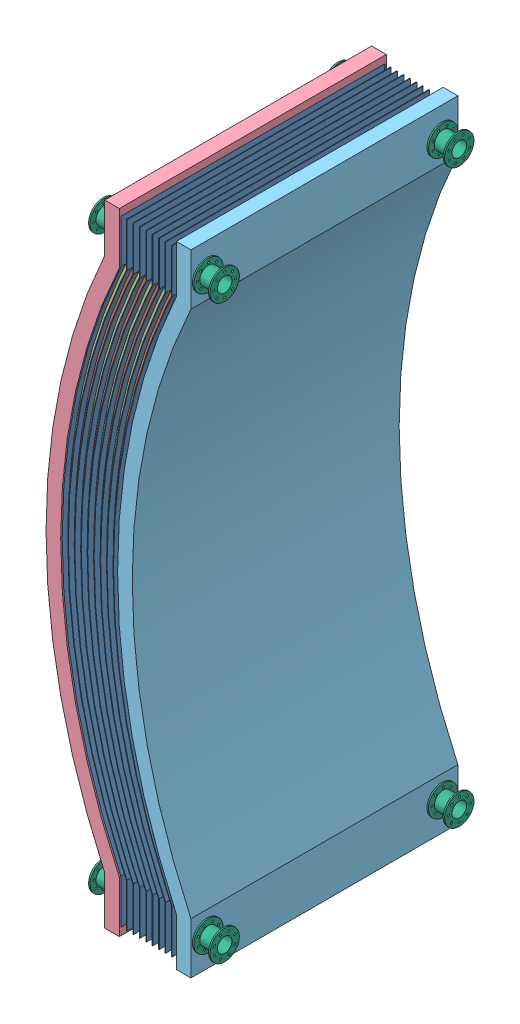
SolidWorks assembly final assembly, configuration Default. Lengths in mm.
Overall size (281.48 1092.2 476.71).
37 component instances, 6 part files, 29 mates.
Components (placement in the parent):
- curved assembly-1: curved assembly [Default] at (-66.7836 46.4861 -15.4947) size (146.36 1066.8 457.2)
  - plate 2-1: plate 2 [Default] at (574.3501 1020.4927 597.4906) size (105.22 1066.8 457.2)
  - plate 2-2: plate 2 [Default] at (585.5261 1020.4927 597.4906) size (105.22 1066.8 457.2)
  - gasket 4-1: gasket 4 [Default] at (584.5101 925.4498 597.4906) size (111.81 1021.08 436.88)
  - plate 2-3: plate 2 [Default] at (596.7021 1020.4927 597.4906) size (105.22 1066.8 457.2)
  - gasket 3-2: gasket 3 [Default] at (595.6861 925.4498 597.4906) size (111.81 1021.08 436.88)
  - plate 2-4: plate 2 [Default] at (607.8781 1020.4927 597.4906) size (105.22 1066.8 457.2)
  - gasket 4-2: gasket 4 [Default] at (606.8621 925.4498 597.4906) size (111.81 1021.08 436.88)
  - gasket 3-3: gasket 3 [Default] at (573.3341 925.4498 597.4906) size (111.81 1021.08 436.88)
- curved assembly-2: curved assembly [Default] at (-22.0796 46.4861 -15.4947) size (146.36 1066.8 457.2)
  - plate 2-1: plate 2 [Default] at (574.3501 1020.4927 597.4906) size (105.22 1066.8 457.2)
  - plate 2-2: plate 2 [Default] at (585.5261 1020.4927 597.4906) size (105.22 1066.8 457.2)
  - gasket 4-1: gasket 4 [Default] at (584.5101 925.4498 597.4906) size (111.81 1021.08 436.88)
  - plate 2-3: plate 2 [Default] at (596.7021 1020.4927 597.4906) size (105.22 1066.8 457.2)
  - gasket 3-2: gasket 3 [Default] at (595.6861 925.4498 597.4906) size (111.81 1021.08 436.88)
  - plate 2-4: plate 2 [Default] at (607.8781 1020.4927 597.4906) size (105.22 1066.8 457.2)
  - gasket 4-2: gasket 4 [Default] at (606.8621 925.4498 597.4906) size (111.81 1021.08 436.88)
  - gasket 3-3: gasket 3 [Default] at (573.3341 925.4498 597.4906) size (111.81 1021.08 436.88)
- curved assembly-3: curved assembly [Default] at (22.6244 46.4861 -15.4947) size (146.36 1066.8 457.2)
  - plate 2-1: plate 2 [Default] at (574.3501 1020.4927 597.4906) size (105.22 1066.8 457.2)
  - plate 2-2: plate 2 [Default] at (585.5261 1020.4927 597.4906) size (105.22 1066.8 457.2)
  - gasket 4-1: gasket 4 [Default] at (584.5101 925.4498 597.4906) size (111.81 1021.08 436.88)
  - plate 2-3: plate 2 [Default] at (596.7021 1020.4927 597.4906) size (105.22 1066.8 457.2)
  - gasket 3-2: gasket 3 [Default] at (595.6861 925.4498 597.4906) size (111.81 1021.08 436.88)
  - plate 2-4: plate 2 [Default] at (607.8781 1020.4927 597.4906) size (105.22 1066.8 457.2)
  - gasket 4-2: gasket 4 [Default] at (606.8621 925.4498 597.4906) size (111.81 1021.08 436.88)
  - gasket 3-3: gasket 3 [Default] at (573.3341 925.4498 597.4906) size (111.81 1021.08 436.88)
- outer 1-1: outer 1 [Default] at (519.2505 971.9359 579.4559) size (127.05 1092.2 462.28)
- outer 2-1: outer 2 [Default] at (643.2025 971.9359 579.4559) size (127.05 1092.2 462.28)
- washer-1: washer [Default] at (465.9105 1010.0359 607.3959) x (0 -0.477528 0.878616) z (-1 0 0) size (50.8 50.8 30.48)
- washer-2: washer [Default] at (465.9105 1010.0359 1013.7959) x (0 -0.747117 0.664692) z (-1 0 0) size (50.8 50.8 30.48)
- washer-3: washer [Default] at (465.9105 19.4359 607.3959) x (0 -0.176929 0.984224) z (-1 0 0) size (50.8 50.8 30.48)
- washer-4: washer [Default] at (465.9105 19.4359 1013.7959) x (0 -0.798753 -0.601659) z (-1 0 0) size (50.8 50.8 30.48)
- washer-5: washer [Default] at (645.7425 1010.0359 1013.7959) x (0 0 1) z (-1 0 0) size (50.8 50.8 30.48)
- washer-6: washer [Default] at (645.7425 1010.0359 607.3959) x (0 -0.414936 0.909851) z (-1 0 0) size (50.8 50.8 30.48)
- washer-7: washer [Default] at (645.7425 19.4359 1013.7959) x (0 -0.38838 0.921499) z (-1 0 0) size (50.8 50.8 30.48)
- washer-8: washer [Default] at (645.7425 19.4359 607.3959) x (0 0.023986 0.999712) z (-1 0 0) size (50.8 50.8 30.48)
Mates (geometry in assembly coordinates):
- Concentric1: concentric: cylinder of assembly; cylinder of assembly; cylinder of curved assembly-1/gasket 4-2 through (82.8785 1010.0359 607.3959) axis (1 0 0) radius 15.24; cylinder of curved assembly-2/gasket 3-3 through (94.0545 1010.0359 607.3959) axis (1 0 0) radius 15.24
- Concentric2: concentric: cylinder of assembly; cylinder of assembly; cylinder of curved assembly-1/gasket 4-2 through (82.8785 1010.0359 1013.7959) axis (1 0 0) radius 15.24; cylinder of curved assembly-2/gasket 3-3 through (94.0545 1010.0359 1013.7959) axis (1 0 0) radius 15.24
- Coincident1: coincident: plane of assembly; plane of assembly; plane of curved assembly-1/plate 2-4 through (541.0945 1048.1359 1039.1959) normal (1 0 0); plane of curved assembly-2/gasket 3-3 through (541.0945 974.1893 1039.1959) normal (-1 0 0)
- Concentric3: concentric: cylinder of assembly; cylinder of assembly; cylinder of curved assembly-2/gasket 4-2 through (127.5825 1010.0359 1013.7959) axis (1 0 0) radius 15.24; cylinder of curved assembly-3/gasket 3-3 through (138.7585 1010.0359 1013.7959) axis (1 0 0) radius 15.24
- Concentric4: concentric: cylinder of assembly; cylinder of assembly; cylinder of curved assembly-2/gasket 4-2 through (127.5825 1010.0359 607.3959) axis (1 0 0) radius 15.24; cylinder of curved assembly-3/gasket 3-3 through (138.7585 1010.0359 607.3959) axis (1 0 0) radius 15.24
- Coincident2: coincident: plane of assembly; plane of assembly; plane of curved assembly-2/plate 2-4 through (585.7985 1048.1359 1039.1959) normal (1 0 0); plane of curved assembly-3/gasket 3-3 through (585.7985 974.1893 1039.1959) normal (-1 0 0)
- Concentric5: concentric: cylinder of assembly; cylinder of assembly; cylinder of curved assembly-1/gasket 4-1 through (964.7665 1010.0359 607.3959) axis (-1 0 0) radius 12.7; cylinder of outer 1-1 through (519.2505 1010.0359 607.3959) axis (-1 0 0) radius 12.7
- Coincident3: coincident: plane of assembly; plane of assembly; plane of curved assembly-1/plate 2-1 through (506.5505 1048.1359 1039.1959) normal (0 1 0); plane of outer 1-1 through (506.5505 1048.1359 1039.1959) normal (0 -1 0)
- Coincident4: coincident: plane of assembly; plane of assembly; plane of curved assembly-1/plate 2-1 through (506.5505 1048.1359 1039.1959) normal (-1 0 0); plane of outer 1-1 through (506.5505 974.7509 1039.1959) normal (1 0 0)
- Concentric8: concentric: cylinder of assembly; cylinder of assembly; cylinder of curved assembly-3/plate 2-4 through (1086.6865 1010.0359 1013.7959) axis (-1 0 0) radius 12.7; cylinder of outer 2-1 through (643.2025 1010.0359 1013.7959) axis (-1 0 0) radius 12.7
- Concentric9: concentric: cylinder of assembly; circle of assembly; cylinder of curved assembly-3/gasket 4-2 through (1076.5265 1010.0359 607.3959) axis (-1 0 0) radius 12.7; circle of outer 2-1
- Parallel2: parallel: plane of assembly; plane of assembly; plane of curved assembly-3/plate 2-4 through (629.4865 1048.1359 1039.1959) normal (0 1 0); plane of outer 2-1 through (617.8025 1060.8359 1041.7359) normal (0 1 0)
- Coincident7: coincident: plane of assembly; plane of assembly; plane of curved assembly-3/plate 2-4 through (630.5025 1048.1359 1039.1959) normal (1 0 0); plane of outer 2-1 through (630.5025 974.7509 1039.1959) normal (-1 0 0)
- Concentric10: concentric: cylinder of assembly; cylinder of assembly; cylinder of outer 1-1 through (519.2505 1010.0359 607.3959) axis (-1 0 0) radius 12.7; cylinder of washer-1 through (463.3705 1010.0359 607.3959) axis (1 0 0) radius 12.7
- Concentric11: concentric: cylinder of assembly; cylinder of assembly; cylinder of outer 1-1 through (519.2505 1010.0359 1013.7959) axis (-1 0 0) radius 12.7; cylinder of washer-2 through (463.3705 1010.0359 1013.7959) axis (1 0 0) radius 12.7
- Coincident11: coincident: plane of assembly; plane of assembly; plane of outer 1-1 through (493.8505 977.5488 1041.7359) normal (-1 0 0); plane of washer-1 through (493.8505 1010.0359 607.3959) normal (1 0 0)
- Coincident12: coincident: plane of assembly; plane of assembly; plane of outer 1-1 through (493.8505 977.5488 1041.7359) normal (-1 0 0); plane of washer-2 through (493.8505 1010.0359 1013.7959) normal (1 0 0)
- Concentric12: concentric: cylinder of assembly; cylinder of assembly; cylinder of curved assembly-1/gasket 4-1 through (964.7665 19.4359 607.3959) axis (-1 0 0) radius 12.7; cylinder of washer-3 through (463.3705 19.4359 607.3959) axis (1 0 0) radius 12.7
- Coincident13: coincident: plane of assembly; plane of assembly; plane of outer 1-1 through (493.8505 51.9229 1041.7359) normal (-1 0 0); plane of washer-3 through (493.8505 19.4359 607.3959) normal (1 0 0)
- Concentric13: concentric: cylinder of assembly; cylinder of assembly; cylinder of curved assembly-1/gasket 4-1 through (964.7665 19.4359 1013.7959) axis (-1 0 0) radius 12.7; cylinder of washer-4 through (463.3705 19.4359 1013.7959) axis (1 0 0) radius 12.7
- Coincident15: coincident: plane of assembly; plane of assembly; plane of outer 1-1 through (493.8505 51.9229 1041.7359) normal (-1 0 0); plane of washer-4 through (493.8505 19.4359 1013.7959) normal (1 0 0)
- Concentric14: concentric: cylinder of assembly; cylinder of assembly; cylinder of outer 2-1 through (643.2025 1010.0359 1013.7959) axis (-1 0 0) radius 12.7; cylinder of washer-5 through (643.2025 1010.0359 1013.7959) axis (1 0 0) radius 12.7
- Coincident16: coincident: plane of assembly; plane of assembly; plane of outer 2-1 through (643.2025 971.9359 1041.7359) normal (1 0 0); plane of washer-5 through (643.2025 1010.0359 1013.7959) normal (-1 0 0)
- Concentric15: concentric: cylinder of assembly; cylinder of assembly; cylinder of outer 2-1 through (643.2025 1010.0359 607.3959) axis (-1 0 0) radius 12.7; cylinder of washer-6 through (643.2025 1010.0359 607.3959) axis (1 0 0) radius 12.7
- Coincident18: coincident: plane of assembly; plane of assembly; plane of outer 2-1 through (643.2025 971.9359 1041.7359) normal (1 0 0); plane of washer-6 through (643.2025 1010.0359 607.3959) normal (-1 0 0)
- Concentric16: concentric: cylinder of assembly; cylinder of assembly; cylinder of outer 2-1 through (643.2025 19.4359 1013.7959) axis (-1 0 0) radius 12.7; cylinder of washer-7 through (643.2025 19.4359 1013.7959) axis (1 0 0) radius 12.7
- Coincident19: coincident: plane of assembly; plane of assembly; plane of outer 2-1 through (643.2025 57.5359 1041.7359) normal (1 0 0); plane of washer-7 through (643.2025 19.4359 1013.7959) normal (-1 0 0)
- Concentric17: concentric: cylinder of assembly; cylinder of assembly; cylinder of outer 2-1 through (643.2025 19.4359 607.3959) axis (-1 0 0) radius 12.7; cylinder of washer-8 through (643.2025 19.4359 607.3959) axis (1 0 0) radius 12.7
- Coincident20: coincident: plane of assembly; plane of assembly; plane of outer 2-1 through (643.2025 57.5359 1041.7359) normal (1 0 0); plane of washer-8 through (643.2025 19.4359 607.3959) normal (-1 0 0)
